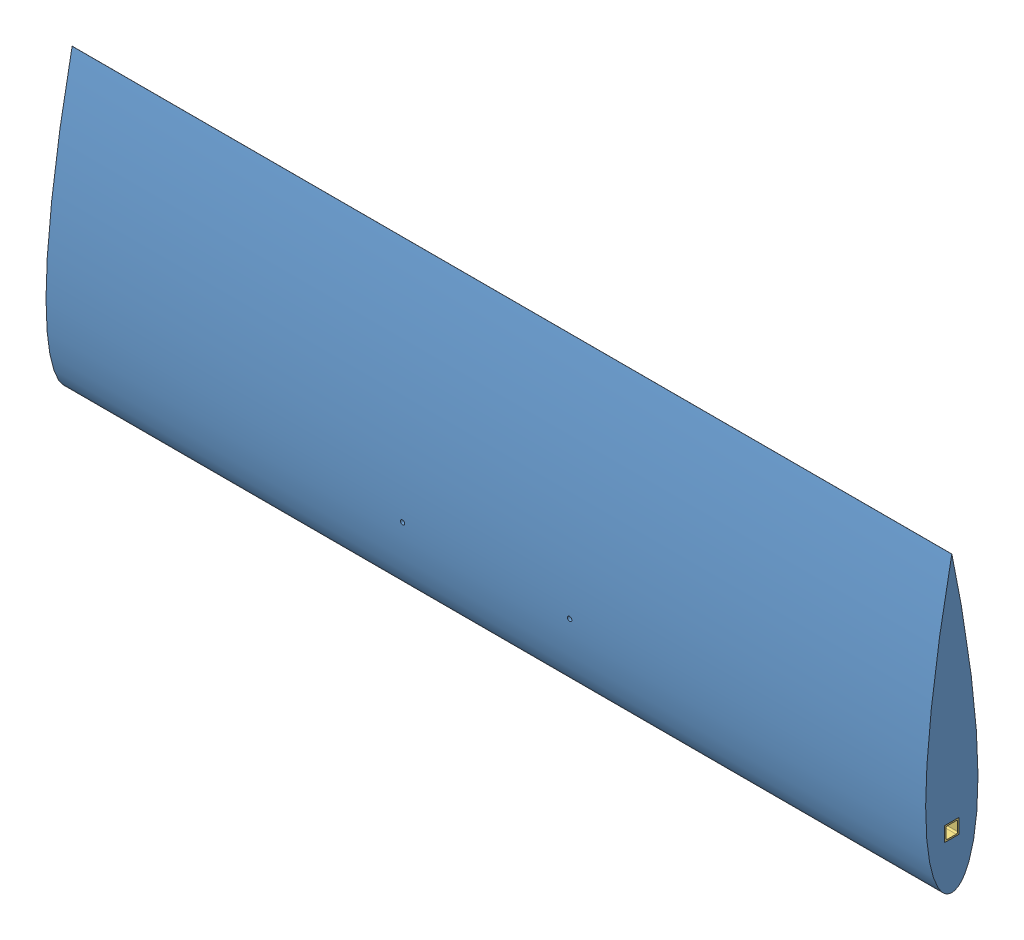
SolidWorks assembly horizontal stabiliser, configuration Default. Lengths in mm.
Overall size (600 201.07 42.21).
23 component instances, 17 part files, 65 mates.
Components (placement in the parent):
- Tail Boom-1: Tail Boom [Default] at (20.2266 -517.2222 1.0272) size (20 1000 20) (hidden)
- Tail holder 1-1: Tail holder 1 [Default] at (31.2437 406.7778 -2.2179) x (1 0 0) z (0 -1 0) size (40 30 124) (hidden)
- tail holder 2-2: tail holder 2 [Default] at (21.0079 496.8403 300.9572) x (0 1 0) z (-1 0 0) size (10 323.08 10) (hidden)
- Tail Boom-2: Tail Boom [Default] at (-93.7734 -517.2222 1.0272) x (-1 0 0) z (0 0 -1) size (20 1000 20) (hidden)
- Tail holder 1-3: Tail holder 1 [Default] at (-104.7904 406.7778 4.2723) x (-1 0 0) z (0 -1 0) size (40 30 124) (hidden)
- Vertical Stabilizer mk1-1: Vertical Stabilizer mk1 [Default] at (20.2266 346.1726 11.0272) x (-1 0 0) z (0 0 1) size (32.74 289.69 300.05) (hidden)
- tail holder 2-3: tail holder 2 [Default] at (-90.2109 492.4966 300.9572) x (1 0 0) z (0 1 0) size (10 323.08 10) (hidden)
- Vertical Stabilizer mk1-2: Vertical Stabilizer mk1 [Default] at (-93.7734 346.1726 11.0272) x (-1 0 0) z (0 0 1) size (32.74 289.69 300.05) (hidden)
- Horisontal stabiliser 11-1: Horisontal stabiliser 11 [Default] at (-336.7734 468.2778 304.1044) x (0 1 0) z (1 0 0) size (201.07 42.21 600)
- top tail holder-1: top tail holder [Default] at (-94.9301 489.7185 257.1044) x (0 -1 0) z (-1 0 0) size (36 23 14)
- top tail holder-3: top tail holder [Default] at (19.0699 489.7185 257.1044) x (0 -1 0) z (-1 0 0) size (36 23 14)
- Horizontal stabilizer bar-1: Horizontal stabilizer bar [Default] at (-336.7734 503.5632 301.2248) x (0 0 -1) z (1 0 0) size (10 10 600)
- Tail motor mount A mk1-1: Tail motor mount A mk1 [Default] at (-97.9309 255.7778 2.925) x (1 0 0) z (0 -1 0) size (55 30 50) (hidden)
- Tail motor mount A mk1-2: Tail motor mount A mk1 [Default] at (24.3842 255.7778 -0.8707) x (-1 0 0) z (0 -1 0) size (55 30 50) (hidden)
- Rear motor crossbar-1: Rear motor crossbar [Default] at (-83.7734 228.9438 2.5044) x (0 1 0) z (1 0 0) size (20 20 94) (hidden)
- Tail motor mount B mk1-1: Tail motor mount B mk1 [Default] at (-38.3549 230.7778 31.0272) x (-1 0 0) z (0 -1 0) size (24 47 40) (hidden)
- Servo mk1-1: Servo mk1 [Default] at (-101.0589 247.0979 -13.9728) x (0.971449 -0.237248 0) z (0.237248 0.971449 0) size (33.6 12.5 34.08) (hidden)
- Flap mk1-1: Flap mk1 [Default] at (-35.9741 313.2778 -18.4266) x (0.996557 0 -0.082916) z (0 -1 0) size (2 40 165) (hidden)
- Servo arm mk1-1: Servo arm mk1 [Default] at (-114.6733 232.8778 17.976) x (-0.995872 0 0.090763) z (0 -1 0) size (10.8 29.4 3.1) (hidden)
- Servo hook mk1-1: Servo hook mk1 [Default] at (-40.7562 235.7778 -42.4932) x (-0.996557 0 0.082916) z (0.082916 0 0.996557) size (6 10 10) (hidden)
- Servo wire-1: Servo wire [Default] at (-102.5419 227.3778 -25.7684) x (-0.039777 0 0.999209) z (0 1 0) size (2 59.28 13) (hidden)
- Tail motor-1: Tail motor [Default] at (-36.7734 230.7778 31.0272) x (-0.55385 -0.832617 0) z (0 0 -1) size (27.5 27.5 31.35) (hidden)
- tail prop-1: tail prop [Default] at (-36.7734 230.7778 54.3772) x (0.926424 -0.376482 0) z (-0.376482 -0.926424 0) size (111.23 11.43 97.73) (hidden)
Mates (geometry in assembly coordinates):
- Distance4: distance = 94 mm anti-aligned: plane of Tail Boom-1 through (10.2266 482.7778 10.0272) normal (-1 0 0); plane of Tail Boom-2 through (-83.7734 482.7778 -7.9728) normal (1 0 0)
- Coincident27: coincident aligned: plane of Tail Boom-1 through (11.2266 482.7778 -8.9728) normal (0 0 -1); plane of Tail Boom-2 through (-84.7734 482.7778 -8.9728) normal (0 0 -1)
- Coincident59: coincident anti-aligned: plane of Tail Boom-2 through (-84.7734 482.7778 -8.9728) normal (0 0 -1); plane of Tail holder 1-3 through (-104.7904 381.7778 -8.9728) normal (0 0 1)
- Coincident60: coincident anti-aligned: plane of Tail Boom-2 through (-103.7734 482.7778 -7.9728) normal (-1 0 0); plane of Tail holder 1-3 through (-103.7734 381.7778 4.2723) normal (1 0 0)
- Parallel1: parallel anti-aligned: plane of Tail Boom-2 through (-83.7734 482.7778 -7.9728) normal (1 0 0); plane of Tail holder 1-3 through (-83.7734 381.7778 4.2723) normal (-1 0 0)
- Coincident63: coincident anti-aligned: plane of Tail Boom-2 through (-84.7734 482.7778 -7.9728) normal (0 1 0); plane of Tail holder 1-3 through (-104.7904 482.7778 4.2723) normal (0 -1 0)
- Coincident64: coincident anti-aligned: plane of Tail Boom-1 through (11.2266 482.7778 10.0272) normal (0 1 0); plane of Tail holder 1-1 through (31.2437 482.7778 -2.2179) normal (0 -1 0)
- Coincident65: coincident anti-aligned: plane of Tail Boom-1 through (10.2266 482.7778 10.0272) normal (-1 0 0); plane of Tail holder 1-1 through (10.2266 381.7778 -2.2179) normal (1 0 0)
- Coincident66: coincident anti-aligned: plane of Tail Boom-1 through (11.2266 482.7778 11.0272) normal (0 0 1); plane of Tail holder 1-1 through (31.2437 381.7778 11.0272) normal (0 0 -1)
- Coincident67: coincident anti-aligned: plane of Tail holder 1-1 through (31.2437 498.2778 110.0272) normal (0 -1 0); plane of tail holder 2-2 through (25.2266 498.2778 -9.0428) normal (0 1 0)
- Coincident68: coincident aligned: plane of Tail holder 1-1 through (31.2437 381.7778 -13.9728) normal (0 0 -1); plane of tail holder 2-2 through (16.2266 489.2778 -13.9728) normal (0 0 -1)
- Coincident69: coincident anti-aligned: plane of Tail holder 1-1 through (15.2266 406.7778 110.0272) normal (1 0 0); plane of tail holder 2-2 through (15.2266 488.2778 -9.0428) normal (-1 0 0)
- Coincident71: coincident aligned: plane of Tail holder 1-3 through (-104.7904 381.7778 -13.9728) normal (0 0 -1); plane of tail holder 2-3 through (-97.7734 497.2778 -13.9728) normal (0 0 -1)
- Coincident72: coincident anti-aligned: plane of Tail holder 1-3 through (-88.7734 406.7778 -107.9728) normal (-1 0 0); plane of tail holder 2-3 through (-88.7734 488.2778 -9.0428) normal (1 0 0)
- Coincident73: coincident anti-aligned: plane of Horisontal stabiliser 11-1 through (-336.7734 486.2778 267.1044) normal (0 1 0); plane of top tail holder-3 through (27.2266 486.2778 297.1044) normal (0 -1 0)
- Coincident74: coincident anti-aligned: plane of Horisontal stabiliser 11-1 through (27.2266 468.2778 267.1044) normal (-1 0 0); plane of top tail holder-3 through (27.2266 500.2778 297.1044) normal (1 0 0)
- Coincident75: coincident anti-aligned: plane of Horisontal stabiliser 11-1 through (-336.7734 468.2778 311.1044) normal (0 0 -1); plane of top tail holder-3 through (19.0699 489.7185 311.1044) normal (0 0 1)
- Coincident76: coincident anti-aligned: plane of Horisontal stabiliser 11-1 through (-100.7734 468.2778 267.1044) normal (1 0 0); plane of top tail holder-1 through (-100.7734 500.2778 297.1044) normal (-1 0 0)
- Coincident77: coincident anti-aligned: plane of Horisontal stabiliser 11-1 through (-336.7734 486.2778 267.1044) normal (0 1 0); plane of top tail holder-1 through (-86.7734 486.2778 297.1044) normal (0 -1 0)
- Coincident78: coincident anti-aligned: plane of Horisontal stabiliser 11-1 through (-336.7734 468.2778 311.1044) normal (0 0 -1); plane of top tail holder-1 through (-94.9301 489.7185 311.1044) normal (0 0 1)
- Coincident81: coincident anti-aligned: plane of Horisontal stabiliser 11-1 through (-390.7734 500.2778 304.1044) normal (0 1 0); plane of Horizontal stabilizer bar-1 through (263.2266 500.2778 309.1044) normal (0 -1 0)
- Coincident83: coincident anti-aligned: plane of Horisontal stabiliser 11-1 through (-390.7734 468.2778 309.1044) normal (0 0 -1); plane of Horizontal stabilizer bar-1 through (263.2266 510.2778 309.1044) normal (0 0 1)
- Coincident84: coincident aligned: plane of Horisontal stabiliser 11-1 through (263.2266 468.2778 304.1044) normal (1 0 0); plane of Horizontal stabilizer bar-1 through (263.2266 503.5632 301.2248) normal (1 0 0)
- Coincident86: coincident anti-aligned: plane of tail holder 2-3 through (-88.7734 488.2778 -9.0428) normal (1 0 0); plane of Vertical Stabilizer mk1-2 through (-88.7734 346.1726 321.0272) normal (-1 0 0)
- Coincident87: coincident anti-aligned: plane of tail holder 2-3 through (-98.7734 488.2778 -9.0428) normal (0 -1 0); plane of Vertical Stabilizer mk1-2 through (-93.7734 488.2778 321.0272) normal (0 1 0)
- Coincident89: coincident anti-aligned: plane of tail holder 2-2 through (25.2266 488.2778 -9.0428) normal (0 -1 0); plane of Vertical stabiliser 11-1 through (20.2266 488.2778 321.0272) normal (0 1 0)
- Coincident90: coincident anti-aligned: plane of tail holder 2-2 through (15.2266 488.2778 -9.0428) normal (-1 0 0); plane of Vertical stabiliser 11-1 through (15.2266 346.1726 321.0272) normal (1 0 0)
- Coincident91: coincident anti-aligned: plane of tail holder 2-2 through (25.2266 488.2778 -9.0428) normal (1 0 0); plane of top tail holder-3 through (25.2266 489.7185 257.1044) normal (-1 0 0)
- Coincident92: coincident anti-aligned: plane of tail holder 2-2 through (25.2266 488.2778 -9.0428) normal (0 -1 0); plane of top tail holder-3 through (19.0699 488.2778 257.1044) normal (0 1 0)
- Distance5: distance = 311.0772 mm: line of top tail holder-1 through (-87.7734 500.2778 297.1044) axis (-1 0 0); plane of tail holder 2-3 through (-97.7734 497.2778 -13.9728) normal (0 0 -1)
- Coincident93: coincident anti-aligned: plane of Tail Boom-1 through (11.2266 482.7778 11.0272) normal (0 0 1); plane of Vertical stabiliser 11-1 through (20.2266 346.1726 11.0272) normal (0 0 -1)
- Coincident94: coincident anti-aligned: plane of Tail Boom-2 through (-84.7734 482.7778 11.0272) normal (0 0 1); plane of Vertical Stabilizer mk1-2 through (-93.7734 346.1726 11.0272) normal (0 0 -1)
- Coincident95: coincident anti-aligned: plane of Tail Boom-2 through (-84.7734 482.7778 -8.9728) normal (0 0 -1); plane of Tail motor mount A mk1-1 through (-103.7734 205.7778 -8.9728) normal (0 0 1)
- Coincident96: coincident anti-aligned: plane of Tail Boom-2 through (-103.7734 482.7778 -7.9728) normal (-1 0 0); plane of Tail motor mount A mk1-1 through (-103.7734 205.7778 11.0272) normal (1 0 0)
- Distance6: distance = 126 mm anti-aligned: plane of Tail holder 1-3 through (-104.7904 381.7778 4.2723) normal (0 -1 0); plane of Tail motor mount A mk1-1 through (-97.9309 255.7778 2.925) normal (0 1 0)
- Coincident98: coincident anti-aligned: plane of Tail Boom-1 through (10.2266 482.7778 10.0272) normal (-1 0 0); plane of Tail motor mount A mk1-2 through (10.2266 205.7778 -8.9728) normal (1 0 0)
- Coincident99: coincident anti-aligned: plane of Tail Boom-1 through (11.2266 482.7778 -8.9728) normal (0 0 -1); plane of Tail motor mount A mk1-2 through (30.2266 205.7778 -8.9728) normal (0 0 1)
- Distance7: distance = 126 mm anti-aligned: plane of Tail holder 1-1 through (31.2437 381.7778 -2.2179) normal (0 -1 0); plane of Tail motor mount A mk1-2 through (24.3842 255.7778 -0.8707) normal (0 1 0)
- Coincident101: coincident anti-aligned: plane of Tail motor mount A mk1-1 through (-103.7734 205.7778 -8.9728) normal (0 0 1); plane of Rear motor crossbar-1 through (10.2266 220.7778 -8.9728) normal (0 0 -1)
- Coincident102: coincident anti-aligned: plane of Tail motor mount A mk1-1 through (-48.7734 240.7778 11.0272) normal (0 -1 0); plane of Rear motor crossbar-1 through (10.2266 240.7778 11.0272) normal (0 1 0)
- Coincident103: coincident anti-aligned: plane of Tail Boom-1 through (10.2266 482.7778 10.0272) normal (-1 0 0); plane of Rear motor crossbar-1 through (10.2266 228.9438 2.5044) normal (1 0 0)
- Coincident104: coincident anti-aligned: plane of Rear motor crossbar-1 through (10.2266 220.7778 -8.9728) normal (0 0 -1); plane of Tail motor mount B mk1-1 through (-9.7734 230.7778 -8.9728) normal (0 0 1)
- Coincident105: coincident anti-aligned: plane of Rear motor crossbar-1 through (10.2266 240.7778 11.0272) normal (0 1 0); plane of Tail motor mount B mk1-1 through (-9.7734 240.7778 31.0272) normal (0 -1 0)
- Distance8: distance = 15 mm anti-aligned: plane of Tail motor mount B mk1-1 through (-48.7734 230.7778 31.0272) normal (-1 0 0); plane of Tail motor mount A mk1-1 through (-63.7734 255.7778 2.925) normal (1 0 0)
- Width2: width anti-aligned: plane of Tail motor mount B mk1-1 through (-38.3549 215.7778 11.0272) normal (0 -1 0); plane of Tail motor mount B mk1-1 through (-38.3549 245.7778 11.0272) normal (0 1 0); plane of Flap mk1-1 through (-35.9741 313.2778 -18.4266) normal (0 1 0); plane of Flap mk1-1 through (-35.9741 148.2778 -18.4266) normal (0 -1 0)
- Coincident109: coincident anti-aligned: line of Tail motor mount B mk1-1 through (-36.7734 215.7778 -15.9728) axis (0 1 0); line of Flap mk1-1 through (-36.7734 313.2778 -15.9728) axis (0 -1 0)
- LimitAngle1: limit planar angle = 1.487785 rad anti-aligned: plane of Flap mk1-1 through (-37.7699 148.2778 -15.8899) normal (-0.996557 0 0.082916); plane of Tail motor mount B mk1-1 through (-9.7734 215.7778 -13.9728) normal (0 0 -1)
- Coincident111: coincident anti-aligned: plane of Tail motor mount A mk1-1 through (-108.7734 205.7778 -13.9728) normal (0 0 -1); plane of Servo mk1-1 through (-101.0589 247.0979 -13.9728) normal (0 0 1)
- Width3: width anti-aligned: plane of Servo mk1-1 through (-105.2734 260.1778 -26.4728) normal (-1 0 0); plane of Servo mk1-1 through (-82.2734 260.1778 -26.4728) normal (1 0 0); plane of Tail motor mount A mk1-1 through (-78.7734 205.7778 16.0272) normal (1 0 0); plane of Tail motor mount A mk1-1 through (-108.7734 205.7778 16.0272) normal (-1 0 0)
- Distance9: distance = 24 mm aligned: plane of Servo mk1-1 through (-101.0589 229.7778 -13.9728) normal (0 -1 0); plane of Tail motor mount A mk1-1 through (-97.9309 205.7778 2.925) normal (0 -1 0)
- Coincident114: coincident anti-aligned: cylinder of Servo mk1-1 through (-99.0234 229.7778 -20.2228) axis (0 1 0) radius 2.4; circle of Servo arm mk1-1
- Coincident115: coincident aligned: plane of Servo mk1-1 through (-101.0589 229.7778 -13.9728) normal (0 -1 0); plane of Servo arm mk1-1 through (-114.6733 229.7778 17.976) normal (0 -1 0)
- Coincident117: coincident anti-aligned: plane of Flap mk1-1 through (-37.7699 148.2778 -15.8899) normal (-0.996557 0 0.082916); plane of Servo hook mk1-1 through (-40.1231 225.7778 -44.1722) normal (0.996557 0 -0.082916)
- Width5: width aligned: plane of Servo hook mk1-1 through (-40.7562 225.7778 -42.4932) normal (0 -1 0); plane of Servo hook mk1-1 through (-40.7562 235.7778 -42.4932) normal (0 1 0); plane of Flap mk1-1 through (-35.9741 148.2778 -18.4266) normal (0 -1 0); plane of Flap mk1-1 through (-35.9741 313.2778 -18.4266) normal (0 1 0)
- Distance12: distance = 11.62 mm aligned: plane of Servo hook mk1-1 through (-40.1231 225.7778 -44.1722) normal (-0.082916 0 -0.996557); plane of Flap mk1-1 through (-41.0866 148.2778 -55.7522) normal (-0.082916 0 -0.996557)
- LimitAngle3: limit planar angle = 1.661685 rad anti-aligned: plane of Servo arm mk1-1 through (-120.1754 229.7778 -42.3945) normal (-0.090763 0 -0.995872); plane of Tail motor mount A mk1-1 through (-108.7734 205.7778 16.0272) normal (-1 0 0)
- Concentric2: concentric aligned: cylinder of Servo arm mk1-1 through (-100.9294 229.7778 -41.1362) axis (0 1 0) radius 1; cylinder of Servo wire-1 through (-100.9294 219.8778 -41.1362) axis (0 1 0) radius 1
- Concentric3: concentric anti-aligned: cylinder of Servo hook mk1-1 through (-43.6947 244.7778 -38.8577) axis (0 -1 0) radius 1; cylinder of Servo wire-1 through (-43.6947 168.0978 -38.8577) axis (0 1 0) radius 1
- Coincident122: coincident aligned: plane of Servo arm mk1-1 through (-114.6733 232.8778 17.976) normal (0 1 0); plane of Servo wire-1 through (-100.9294 232.8778 -41.1362) normal (0 1 0)
- Coincident123: coincident anti-aligned: plane of Tail holder 1-3 through (-104.7904 488.2778 -107.9728) normal (0 1 0); plane of tail holder 2-3 through (-98.7734 488.2778 -9.0428) normal (0 -1 0)
- Coincident125: coincident anti-aligned: plane of Tail motor mount A mk1-2 through (-24.7734 240.7778 -8.9728) normal (0 -1 0); plane of Rear motor crossbar-1 through (10.2266 240.7778 11.0272) normal (0 1 0)
- Concentric13: concentric aligned: cylinder of Tail motor mount B mk1-1 through (-36.7734 230.7778 26.0272) axis (0 0 1) radius 11; cylinder of Tail motor-1 through (-36.7734 230.7778 62.3772) axis (0 0 1) radius 13.75
- Coincident126: coincident anti-aligned: plane of Tail motor mount B mk1-1 through (-38.3549 230.7778 31.0272) normal (0 0 1); plane of Tail motor-1 through (-36.7734 230.7778 31.0272) normal (0 0 -1)
- Concentric14: concentric anti-aligned: cylinder of Tail motor-1 through (-36.7734 230.7778 62.3772) axis (0 0 1) radius 2.5; cylinder of tail prop-1 through (-36.7734 230.7778 62.3772) axis (0 0 -1) radius 2.5
- Coincident127: coincident aligned: plane of Tail motor-1 through (-38.158 228.6963 62.3772) normal (0 0 1); plane of tail prop-1 through (-36.7734 230.7778 62.3772) normal (0 0 1)
